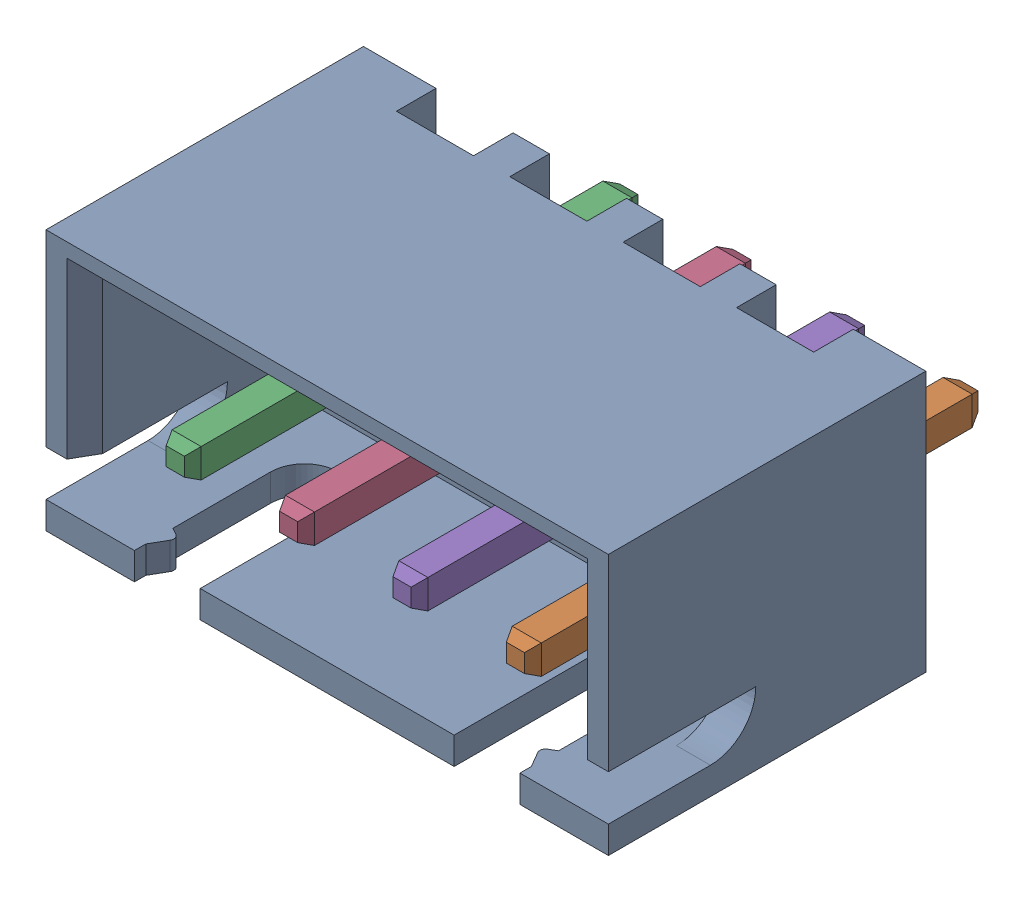
SolidWorks assembly JST-XH-4POS-VERT_1, configuration Default. Lengths in mm.
Overall size (12.4 5.75 10.4).
5 component instances, 2 part files, 0 mates.
Components (placement in the parent):
- Plastic_1-1: Plastic_1 [Default] at (0 -2.875 0) size (12.4 5.75 7)
- Pin_1-5: Pin_1 [Default] at (3.75 -0.525 1.6) size (0.64 0.64 10)
- Pin_1-6: Pin_1 [Default] at (-3.75 -0.525 1.6) size (0.64 0.64 10)
- Pin_1-7: Pin_1 [Default] at (-1.25 -0.525 1.6) size (0.64 0.64 10)
- Pin_1-4: Pin_1 [Default] at (1.25 -0.525 1.6) size (0.64 0.64 10)
